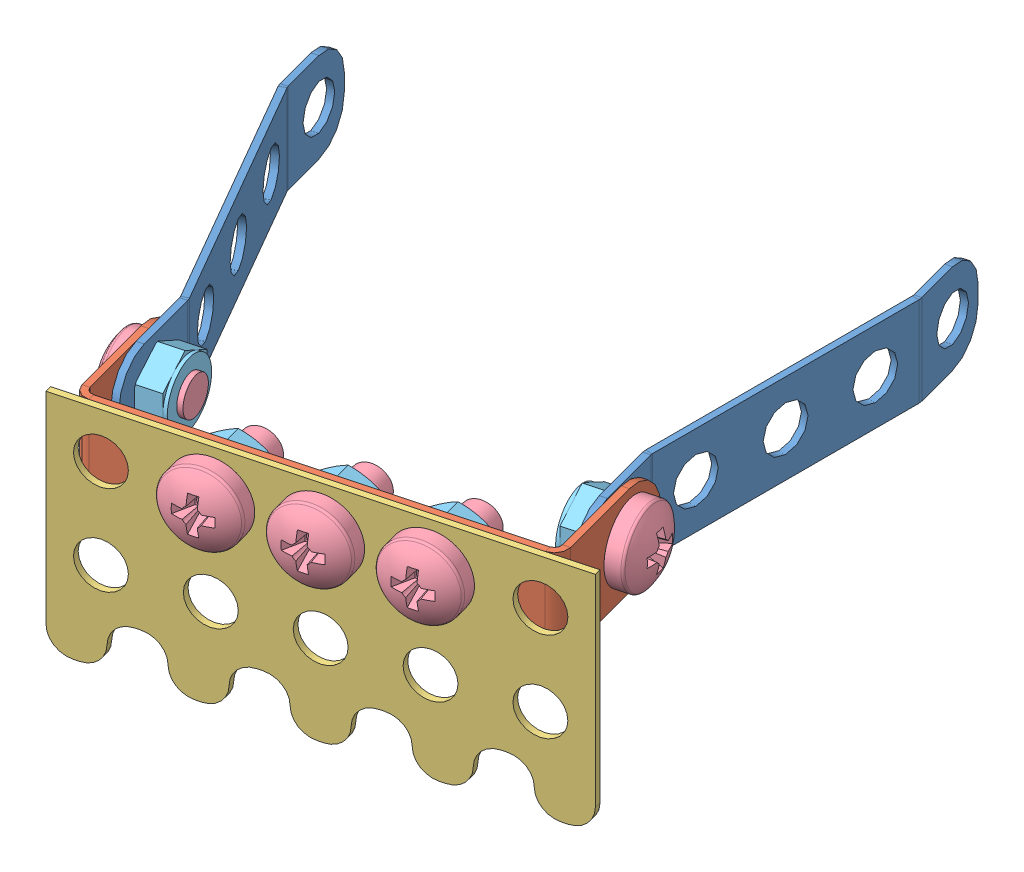
SolidWorks assembly RZ-R1-2003-1, configuration По умолчанию. Lengths in mm.
Overall size (71.73 25 66.49).
14 component instances, 5 part files, 23 mates.
Components (placement in the parent):
- RZ-R1-4011-1-1: RZ-R1-4011-1 [По умолчанию] at (29.2581 27.1086 29.8673) x (0 1 0) z (0 0 1) size (10 5.89 49.51)
- RZ-R1-4012-1-1: RZ-R1-4012-1 [По умолчанию] at (13.2039 22.1086 63.7985) x (0.965926 0 -0.258819) z (0 1 0) size (44.47 15.74 10)
- RZ-R1-4013-1-1: RZ-R1-4013-1 [По умолчанию] at (14.3226 19.6086 65.0239) x (0.965926 0 -0.258819) z (0 -1 0) size (50 0.74 25)
- RZ-R1-4011-1-3: RZ-R1-4011-1 [По умолчанию] at (-17.7717 27.1086 42.4689) x (0 -1 0) z (0.5 0 0.866025) size (10 5.89 49.51)
- pan head cross recess screw_iso-11: pan head cross recess screw_iso [ISO 7045 - M4 x 8 - Z --- 8N] at (15.1249 27.1086 68.0183) x (-0.258819 0 -0.965926) z (0.965926 0 -0.258819) size (11.02 8 8)
- pan head cross recess screw_iso-12: pan head cross recess screw_iso [ISO 7045 - M4 x 8 - Z --- 8N] at (5.4657 27.1086 70.6065) x (-0.258819 0 -0.965926) z (0.965926 0 -0.258819) size (11.02 8 8)
- pan head cross recess screw_iso-13: pan head cross recess screw_iso [ISO 7045 - M4 x 8 - Z --- 8N] at (24.7842 27.1086 65.4301) x (-0.258819 0 -0.965926) z (0.965926 0 -0.258819) size (11.02 8 8)
- hex nut style 1 gradeab_iso-14: hex nut style 1 gradeab_iso [Hexagon Nut ISO - 4032 - M4 - W - N] at (13.1131 27.1086 60.51) x (-0.965926 0 0.258819) z (-0.258819 0 -0.965926) size (7 8.08 3.2)
- hex nut style 1 gradeab_iso-15: hex nut style 1 gradeab_iso [Hexagon Nut ISO - 4032 - M4 - W - N] at (3.4538 27.1086 63.0982) x (-0.965926 0 0.258819) z (-0.258819 0 -0.965926) size (7 8.08 3.2)
- hex nut style 1 gradeab_iso-16: hex nut style 1 gradeab_iso [Hexagon Nut ISO - 4032 - M4 - W - N] at (22.7723 27.1086 57.9218) x (-0.965926 0 0.258819) z (-0.258819 0 -0.965926) size (7 8.08 3.2)
- pan head cross recess screw_iso-16: pan head cross recess screw_iso [ISO 7045 - M4 x 5 - Z --- 5N] at (35.089 27.1086 47.5817) x (-0.965926 0 0.258819) z (-0.258819 0 -0.965926) size (8.02 8 8)
- pan head cross recess screw_iso-17: pan head cross recess screw_iso [ISO 7045 - M4 x 5 - Z --- 5N] at (-13.8576 27.1086 60.6968) x (0.965926 0 -0.258819) z (0.258819 0 0.965926) size (8.02 8 8)
- hex nut style 1 gradeab_iso-17: hex nut style 1 gradeab_iso [Hexagon Nut ISO - 4032 - M4 - W - N] at (30.6538 27.1086 48.7701) x (-0.258819 0 -0.965926) z (0.965926 0 -0.258819) size (7 8.08 3.2)
- hex nut style 1 gradeab_iso-18: hex nut style 1 gradeab_iso [Hexagon Nut ISO - 4032 - M4 - W - N] at (-9.6738 27.1086 59.5758) x (0.258819 0 0.965926) z (-0.965926 0 0.258819) size (7 8.08 3.2)
Mates (geometry in assembly coordinates):
- Концентричный3: concentric anti-aligned: circle of RZ-R1-4011-1-1; circle of RZ-R1-4012-1-1
- Совпадение3: coincident anti-aligned: plane of RZ-R1-4012-1-1 through (-11.4458 32.1086 54.8742) normal (0.965926 0 -0.258819); plane of RZ-R1-4011-1-3 through (-15.0693 27.1086 41.3513) normal (-0.965926 0 0.258819)
- Концентричный4: concentric aligned: circle of RZ-R1-4012-1-1; circle of RZ-R1-4013-1-1
- Концентричный5: concentric aligned: circle of RZ-R1-4012-1-1; circle of RZ-R1-4013-1-1
- Совпадение6: coincident anti-aligned: plane of RZ-R1-4012-1-1 through (-7.3729 32.1086 70.0746) normal (0.258819 0 0.965926); plane of RZ-R1-4013-1-1 through (14.1319 19.6086 64.3124) normal (-0.258819 0 -0.965926)
- Концентричный381: concentric anti-aligned: cylinder of RZ-R1-4012-1-1 through (14.1322 27.1086 64.3134) axis (-0.258819 0 -0.965926) radius 2.5; cylinder of pan head cross recess screw_iso-11 through (21.6989 27.1086 92.5528) axis (0.258819 0 0.965926) radius 2
- Совпадение421: coincident anti-aligned: plane of RZ-R1-4013-1-1 through (14.3226 19.6086 65.0239) normal (0.258819 0 0.965926); plane of pan head cross recess screw_iso-11 through (14.3226 29.1086 65.0239) normal (-0.258819 0 -0.965926)
- Концентричный391: concentric anti-aligned: cylinder of RZ-R1-4012-1-1 through (4.4729 27.1086 66.9016) axis (-0.258819 0 -0.965926) radius 2.5; cylinder of pan head cross recess screw_iso-12 through (12.0397 27.1086 95.141) axis (0.258819 0 0.965926) radius 2
- Совпадение431: coincident anti-aligned: plane of RZ-R1-4013-1-1 through (14.3226 19.6086 65.0239) normal (0.258819 0 0.965926); plane of pan head cross recess screw_iso-12 through (4.6633 29.1086 67.6121) normal (-0.258819 0 -0.965926)
- Концентричный401: concentric aligned: cylinder of RZ-R1-4013-1-1 through (23.7909 27.1086 61.7233) axis (0.258819 0 0.965926) radius 2.5; cylinder of pan head cross recess screw_iso-13 through (31.3582 27.1086 89.9646) axis (0.258819 0 0.965926) radius 2
- Совпадение441: coincident anti-aligned: plane of RZ-R1-4013-1-1 through (14.3226 19.6086 65.0239) normal (0.258819 0 0.965926); plane of pan head cross recess screw_iso-13 through (23.9818 29.1086 62.4357) normal (-0.258819 0 -0.965926)
- Концентричный41: concentric anti-aligned: cylinder of pan head cross recess screw_iso-11 through (21.6989 27.1086 92.5528) axis (0.258819 0 0.965926) radius 2; cylinder of hex nut style 1 gradeab_iso-14 through (19.5932 27.1086 84.6943) axis (-0.258819 0 -0.965926) radius 2
- Совпадение45: coincident anti-aligned: plane of RZ-R1-4012-1-1 through (-7.5635 32.1086 69.3631) normal (-0.258819 0 -0.965926); plane of hex nut style 1 gradeab_iso-14 through (13.9413 31.15 63.6009) normal (0.258819 0 0.965926)
- Концентричный42: concentric anti-aligned: cylinder of pan head cross recess screw_iso-12 through (12.0397 27.1086 95.141) axis (0.258819 0 0.965926) radius 2; cylinder of hex nut style 1 gradeab_iso-15 through (9.934 27.1086 87.2825) axis (-0.258819 0 -0.965926) radius 2
- Совпадение46: coincident anti-aligned: plane of RZ-R1-4012-1-1 through (-7.5635 32.1086 69.3631) normal (-0.258819 0 -0.965926); plane of hex nut style 1 gradeab_iso-15 through (4.282 31.15 66.1891) normal (0.258819 0 0.965926)
- Концентричный43: concentric anti-aligned: cylinder of pan head cross recess screw_iso-13 through (31.3582 27.1086 89.9646) axis (0.258819 0 0.965926) radius 2; cylinder of hex nut style 1 gradeab_iso-16 through (29.2525 27.1086 82.1062) axis (-0.258819 0 -0.965926) radius 2
- Совпадение47: coincident anti-aligned: plane of RZ-R1-4012-1-1 through (-7.5635 32.1086 69.3631) normal (-0.258819 0 -0.965926); plane of hex nut style 1 gradeab_iso-16 through (23.6005 31.15 61.0127) normal (0.258819 0 0.965926)
- Концентричный44: concentric aligned: cylinder of RZ-R1-4012-1-1 through (-10.8632 27.1086 59.8945) axis (0.965926 0 -0.258819) radius 2.5; cylinder of pan head cross recess screw_iso-16 through (59.6235 27.1086 41.0077) axis (0.965926 0 -0.258819) radius 4
- Совпадение48: coincident anti-aligned: plane of RZ-R1-4012-1-1 through (34.6828 32.1086 58.0433) normal (0.965926 0 -0.258819); plane of pan head cross recess screw_iso-16 through (32.0946 29.1086 48.384) normal (-0.965926 0 0.258819)
- Концентричный45: concentric anti-aligned: cylinder of RZ-R1-4012-1-1 through (-10.8632 27.1086 59.8945) axis (0.965926 0 -0.258819) radius 2.5; cylinder of pan head cross recess screw_iso-17 through (-38.3921 27.1086 67.2709) axis (-0.965926 0 0.258819) radius 4
- Совпадение49: coincident anti-aligned: plane of RZ-R1-4012-1-1 through (-12.1573 32.1086 55.0649) normal (-0.965926 0 0.258819); plane of pan head cross recess screw_iso-17 through (-10.8632 29.1086 59.8945) normal (0.965926 0 -0.258819)
- Концентричный46: concentric aligned: cylinder of pan head cross recess screw_iso-16 through (59.6235 27.1086 41.0077) axis (0.965926 0 -0.258819) radius 2; cylinder of hex nut style 1 gradeab_iso-17 through (6.4695 27.1086 55.2502) axis (0.965926 0 -0.258819) radius 2
- Концентричный47: concentric aligned: cylinder of pan head cross recess screw_iso-17 through (-38.3921 27.1086 67.2709) axis (-0.965926 0 0.258819) radius 2; cylinder of hex nut style 1 gradeab_iso-18 through (14.5106 27.1086 53.0956) axis (-0.965926 0 0.258819) radius 2
